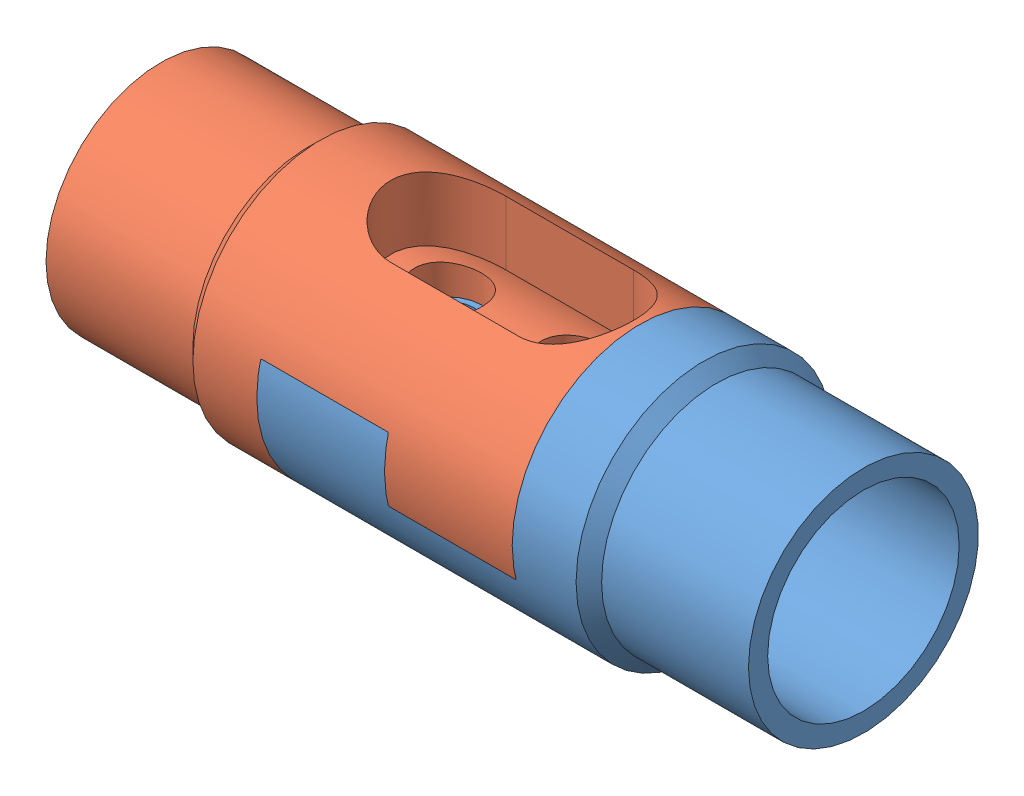
SolidWorks assembly Assemblage tube interloocking , configuration Défaut. Lengths in mm.
Overall size (110 40.01 40).
2 component instances, 2 part files, 3 mates.
Components (placement in the parent):
- Tube interlocking -2: Tube interlocking  [Défaut] at (86.9081 5.9422 75) size (75 40 40)
- Tube interlocking  2-3: Tube interlocking  2 [Défaut] at (-66.5331 -15.0656 75) x (-1 0 0) z (0 0 1) size (75 40.01 40)
Mates (geometry in assembly coordinates):
- Verrouiller1: lock: unknown of Tube interlocking -2
- Distance1: distance = 0 mm: line of Tube interlocking  2-3 through (10.3875 -9.5617 94.3649) axis (1 0 0); line of Tube interlocking -2 through (29.9875 -9.5617 94.3649) axis (-1 0 0)
- Coïncidente1: coincident aligned: circle of Tube interlocking -2; circle of Tube interlocking  2-3
